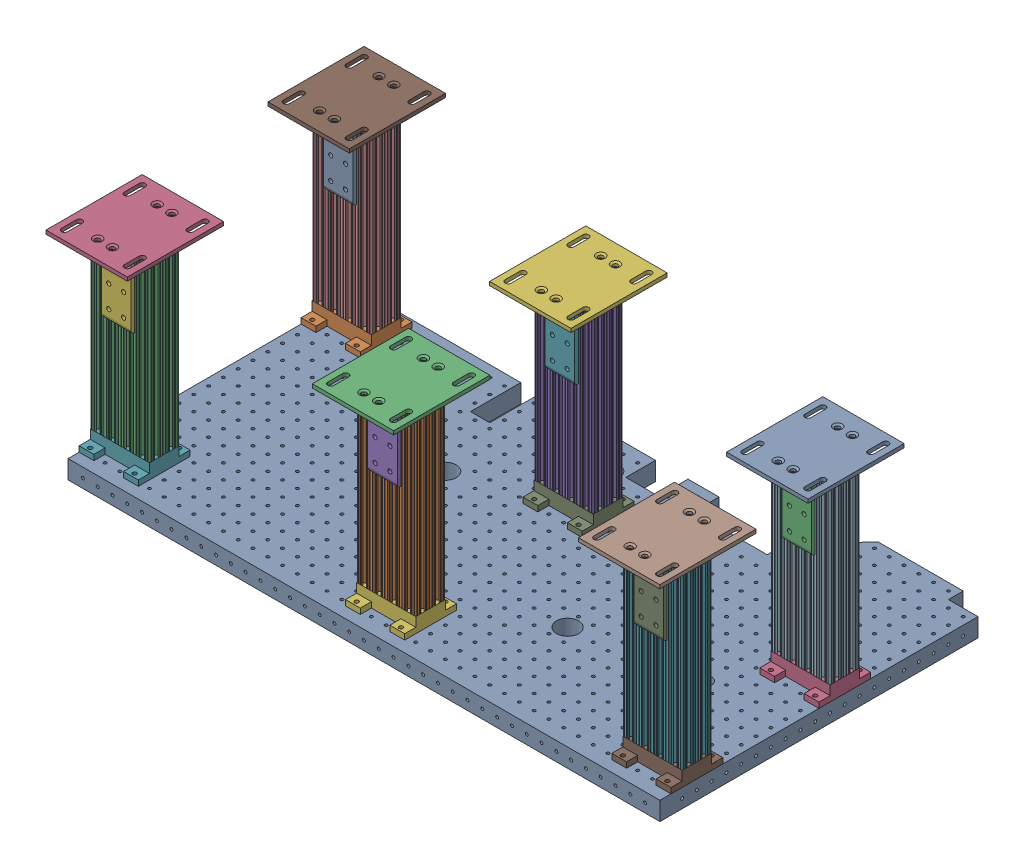
SolidWorks assembly Mirrorbreadboard 2 assembly, configuration Default. Lengths in mm.
Overall size (1054.1 371.48 590.75).
43 component instances, 5 part files, 18 mates.
Components (placement in the parent):
- MirrorBreadboard1-2: MirrorBreadboard1 [Default] at (-194.6573 17.0814 -91.1131) size (1016 31.75 571.5)
- Mirrorbreadboard support leg assembly-2: Mirrorbreadboard support leg assembly [Default] at (-182.8187 304.0452 389.5924) x (0 0 1) z (0 -1 0) size (165.1 139.7 339.72)
  - Mirror8020-2040 leg for breadboard support-1: Mirror8020-2040 leg for breadboard support [Default] at (-48.9055 -77.0614 -78.1612) size (50.8 101.6 307.98)
  - Mirror8020-2387-DEFAULT-1: Mirror8020-2387-DEFAULT [Default] at (-34.9863 -22.6888 -91.8816) x (0 1 0) z (1 0 0) size (139.7 133.35 165.1)
    - Mirror8020-2387-DEFAULT_238708-1: Mirror8020-2387-DEFAULT_238708 [Default] at (-67.1549 7.3704 -27.8119) size (139.7 6.35 165.1)
    - Mirror8020-2387-DEFAULT_238509-1: Mirror8020-2387-DEFAULT_238509 [Default] at (9.1264 0.0214 -49.7635) x (0 0 -1) z (1 0 0) size (50.8 127 50.8)
    - Mirror8020-2387-DEFAULT_238509-2: Mirror8020-2387-DEFAULT_238509 [Default] at (-41.6736 0.0214 46.9187) x (0 0 1) z (-1 0 0) size (50.8 127 50.8)
  - Mirrorbreadboard support leg top bracket-1: Mirrorbreadboard support leg top bracket [Default] at (-61.6055 -89.7614 229.8138) x (0 1 0) z (1 0 0) size (101.6 25.4 88.9)
- Mirrorbreadboard support leg assembly1-2: Mirrorbreadboard support leg assembly1 [Default] at (352.3041 304.0452 317.1813) x (0 0 -1) z (0 -1 0) size (165.1 139.7 339.72)
  - Mirror8020-2040 leg for breadboard support-1: Mirror8020-2040 leg for breadboard support [Default] at (-48.9055 -77.0614 -78.1612) size (50.8 101.6 307.98)
  - Mirror8020-2387-DEFAULT1-1: Mirror8020-2387-DEFAULT1 [Default] at (-34.9863 -22.6888 -91.8816) x (0 1 0) z (1 0 0) size (139.7 133.35 165.1)
    - Mirror8020-2387-DEFAULT_238708-1: Mirror8020-2387-DEFAULT_238708 [Default] at (-67.1549 7.3704 -27.8119) size (139.7 6.35 165.1)
    - Mirror8020-2387-DEFAULT_238509-1: Mirror8020-2387-DEFAULT_238509 [Default] at (9.1264 0.0214 -49.7635) x (0 0 -1) z (1 0 0) size (50.8 127 50.8)
    - Mirror8020-2387-DEFAULT_238509-2: Mirror8020-2387-DEFAULT_238509 [Default] at (-41.6736 0.0214 46.9187) x (0 0 1) z (-1 0 0) size (50.8 127 50.8)
  - Mirrorbreadboard support leg top bracket-1: Mirrorbreadboard support leg top bracket [Default] at (-61.6055 -89.7614 229.8138) x (0 1 0) z (1 0 0) size (101.6 25.4 88.9)
- Mirrorbreadboard support leg assembly2-3: Mirrorbreadboard support leg assembly2 [Default] at (274.3813 304.0452 135.5924) x (0 0 1) z (0 -1 0) size (165.1 139.7 339.72)
  - Mirror8020-2040 leg for breadboard support-1: Mirror8020-2040 leg for breadboard support [Default] at (-48.9055 -77.0614 -78.1612) size (50.8 101.6 307.98)
  - Mirror8020-2387-DEFAULT2-1: Mirror8020-2387-DEFAULT2 [Default] at (-34.9863 -22.6888 -91.8816) x (0 1 0) z (1 0 0) size (139.7 133.35 165.1)
    - Mirror8020-2387-DEFAULT_238708-1: Mirror8020-2387-DEFAULT_238708 [Default] at (-67.1549 7.3704 -27.8119) size (139.7 6.35 165.1)
    - Mirror8020-2387-DEFAULT_238509-1: Mirror8020-2387-DEFAULT_238509 [Default] at (9.1264 0.0214 -49.7635) x (0 0 -1) z (1 0 0) size (50.8 127 50.8)
    - Mirror8020-2387-DEFAULT_238509-2: Mirror8020-2387-DEFAULT_238509 [Default] at (-41.6736 0.0214 46.9187) x (0 0 1) z (-1 0 0) size (50.8 127 50.8)
  - Mirrorbreadboard support leg top bracket-1: Mirrorbreadboard support leg top bracket [Default] at (-61.6055 -89.7614 229.8138) x (0 1 0) z (1 0 0) size (101.6 25.4 88.9)
- Mirrorbreadboard support leg assembly3-4: Mirrorbreadboard support leg assembly3 [Default] at (-104.8959 304.0452 12.3813) x (0 0 -1) z (0 -1 0) size (165.1 139.7 339.72)
  - Mirror8020-2040 leg for breadboard support-1: Mirror8020-2040 leg for breadboard support [Default] at (-48.9055 -77.0614 -78.1612) size (50.8 101.6 307.98)
  - Mirror8020-2387-DEFAULT3-1: Mirror8020-2387-DEFAULT3 [Default] at (-34.9863 -22.6888 -91.8816) x (0 1 0) z (1 0 0) size (139.7 133.35 165.1)
    - Mirror8020-2387-DEFAULT_238708-1: Mirror8020-2387-DEFAULT_238708 [Default] at (-67.1549 7.3704 -27.8119) size (139.7 6.35 165.1)
    - Mirror8020-2387-DEFAULT_238509-1: Mirror8020-2387-DEFAULT_238509 [Default] at (9.1264 0.0214 -49.7635) x (0 0 -1) z (1 0 0) size (50.8 127 50.8)
    - Mirror8020-2387-DEFAULT_238509-2: Mirror8020-2387-DEFAULT_238509 [Default] at (-41.6736 0.0214 46.9187) x (0 0 1) z (-1 0 0) size (50.8 127 50.8)
  - Mirrorbreadboard support leg top bracket-1: Mirrorbreadboard support leg top bracket [Default] at (-61.6055 -89.7614 229.8138) x (0 1 0) z (1 0 0) size (101.6 25.4 88.9)
- Mirrorbreadboard support leg assembly4-5: Mirrorbreadboard support leg assembly4 [Default] at (-640.0187 304.0452 8.5924) x (0 0 1) z (0 -1 0) size (165.1 139.7 339.72)
  - Mirror8020-2040 leg for breadboard support-1: Mirror8020-2040 leg for breadboard support [Default] at (-48.9055 -77.0614 -78.1612) size (50.8 101.6 307.98)
  - Mirror8020-2387-DEFAULT4-1: Mirror8020-2387-DEFAULT4 [Default] at (-34.9863 -22.6888 -91.8816) x (0 1 0) z (1 0 0) size (139.7 133.35 165.1)
    - Mirror8020-2387-DEFAULT_238708-1: Mirror8020-2387-DEFAULT_238708 [Default] at (-67.1549 7.3704 -27.8119) size (139.7 6.35 165.1)
    - Mirror8020-2387-DEFAULT_238509-1: Mirror8020-2387-DEFAULT_238509 [Default] at (9.1264 0.0214 -49.7635) x (0 0 -1) z (1 0 0) size (50.8 127 50.8)
    - Mirror8020-2387-DEFAULT_238509-2: Mirror8020-2387-DEFAULT_238509 [Default] at (-41.6736 0.0214 46.9187) x (0 0 1) z (-1 0 0) size (50.8 127 50.8)
  - Mirrorbreadboard support leg top bracket-1: Mirrorbreadboard support leg top bracket [Default] at (-61.6055 -89.7614 229.8138) x (0 1 0) z (1 0 0) size (101.6 25.4 88.9)
- Mirrorbreadboard support leg assembly5-6: Mirrorbreadboard support leg assembly5 [Default] at (-640.0187 304.0452 389.5924) x (0 0 1) z (0 -1 0) size (165.1 139.7 339.72)
  - Mirror8020-2040 leg for breadboard support-1: Mirror8020-2040 leg for breadboard support [Default] at (-48.9055 -77.0614 -78.1612) size (50.8 101.6 307.98)
  - Mirror8020-2387-DEFAULT5-1: Mirror8020-2387-DEFAULT5 [Default] at (-34.9863 -22.6888 -91.8816) x (0 1 0) z (1 0 0) size (139.7 133.35 165.1)
    - Mirror8020-2387-DEFAULT_238708-1: Mirror8020-2387-DEFAULT_238708 [Default] at (-67.1549 7.3704 -27.8119) size (139.7 6.35 165.1)
    - Mirror8020-2387-DEFAULT_238509-1: Mirror8020-2387-DEFAULT_238509 [Default] at (9.1264 0.0214 -49.7635) x (0 0 -1) z (1 0 0) size (50.8 127 50.8)
    - Mirror8020-2387-DEFAULT_238509-2: Mirror8020-2387-DEFAULT_238509 [Default] at (-41.6736 0.0214 46.9187) x (0 0 1) z (-1 0 0) size (50.8 127 50.8)
  - Mirrorbreadboard support leg top bracket-1: Mirrorbreadboard support leg top bracket [Default] at (-61.6055 -89.7614 229.8138) x (0 1 0) z (1 0 0) size (101.6 25.4 88.9)
Mates (geometry in assembly coordinates):
- Coincident1: coincident anti-aligned: plane of MirrorBreadboard1-2 through (-194.6573 48.8314 416.8869) normal (0 1 0); plane of Mirrorbreadboard support leg assembly-2/Mirrorbreadboard support leg top bracket-1 through (-93.0573 48.8314 378.7869) normal (0 -1 0)
- Parallel1: parallel aligned: plane of MirrorBreadboard1-2 through (-651.8573 17.0814 416.8869) normal (-1 0 0); plane of Mirrorbreadboard support leg assembly-2/Mirrorbreadboard support leg top bracket-1 through (-194.6573 48.8314 327.9869) normal (-1 0 0)
- Coincident2: coincident anti-aligned: plane of MirrorBreadboard1-2 through (-194.6573 48.8314 416.8869) normal (0 1 0); plane of Mirrorbreadboard support leg assembly3-4/Mirrorbreadboard support leg top bracket-1 through (-194.6573 48.8314 23.1869) normal (0 -1 0)
- Parallel2: parallel anti-aligned: plane of MirrorBreadboard1-2 through (-194.6573 48.8314 416.8869) normal (0 0 1); plane of Mirrorbreadboard support leg assembly3-4/Mirrorbreadboard support leg top bracket-1 through (-93.0573 58.3564 4.1369) normal (0 0 -1)
- Coincident3: coincident anti-aligned: plane of MirrorBreadboard1-2 through (-194.6573 48.8314 416.8869) normal (0 1 0); plane of Mirrorbreadboard support leg assembly2-3/Mirrorbreadboard support leg top bracket-1 through (364.1427 48.8314 124.7869) normal (0 -1 0)
- Coincident4: coincident anti-aligned: plane of MirrorBreadboard1-2 through (-194.6573 48.8314 416.8869) normal (0 1 0); plane of Mirrorbreadboard support leg assembly1-2/Mirrorbreadboard support leg top bracket-1 through (262.5427 48.8314 327.9869) normal (0 -1 0)
- Coincident5: coincident aligned: plane of MirrorBreadboard1-2 through (364.1427 48.8314 -91.1131) normal (1 0 0); plane of Mirrorbreadboard support leg assembly1-2/Mirrorbreadboard support leg top bracket-1 through (364.1427 48.8314 378.7869) normal (1 0 0)
- Concentric1: concentric anti-aligned: circle of MirrorBreadboard1-2; circle of Mirrorbreadboard support leg assembly1-2/Mirrorbreadboard support leg top bracket-1
- Concentric2: concentric anti-aligned: circle of MirrorBreadboard1-2; circle of Mirrorbreadboard support leg assembly3-4/Mirrorbreadboard support leg top bracket-1
- Concentric3: concentric anti-aligned: circle of MirrorBreadboard1-2; circle of Mirrorbreadboard support leg assembly-2/Mirrorbreadboard support leg top bracket-1
- Concentric4: concentric anti-aligned: circle of MirrorBreadboard1-2; circle of Mirrorbreadboard support leg assembly2-3/Mirrorbreadboard support leg top bracket-1
- Parallel3: parallel aligned: plane of MirrorBreadboard1-2 through (364.1427 48.8314 -91.1131) normal (1 0 0); plane of Mirrorbreadboard support leg assembly2-3/Mirrorbreadboard support leg top bracket-1 through (364.1427 48.8314 73.9869) normal (1 0 0)
- Coincident6: coincident anti-aligned: plane of MirrorBreadboard1-2 through (-194.6573 48.8314 416.8869) normal (0 1 0); plane of Mirrorbreadboard support leg assembly4-5/Mirrorbreadboard support leg top bracket-1 through (-550.2573 48.8314 -2.2131) normal (0 -1 0)
- Concentric5: concentric anti-aligned: circle of MirrorBreadboard1-2; circle of Mirrorbreadboard support leg assembly4-5/Mirrorbreadboard support leg top bracket-1
- Parallel4: parallel aligned: plane of MirrorBreadboard1-2 through (-651.8573 17.0814 416.8869) normal (-1 0 0); plane of Mirrorbreadboard support leg assembly4-5/Mirrorbreadboard support leg top bracket-1 through (-651.8573 48.8314 -53.0131) normal (-1 0 0)
- Coincident7: coincident anti-aligned: plane of MirrorBreadboard1-2 through (-194.6573 48.8314 416.8869) normal (0 1 0); plane of Mirrorbreadboard support leg assembly5-6/Mirrorbreadboard support leg top bracket-1 through (-550.2573 48.8314 378.7869) normal (0 -1 0)
- Concentric6: concentric anti-aligned: circle of MirrorBreadboard1-2; circle of Mirrorbreadboard support leg assembly5-6/Mirrorbreadboard support leg top bracket-1
- Parallel5: parallel aligned: plane of MirrorBreadboard1-2 through (-651.8573 17.0814 416.8869) normal (-1 0 0); plane of Mirrorbreadboard support leg assembly5-6/Mirrorbreadboard support leg top bracket-1 through (-651.8573 48.8314 327.9869) normal (-1 0 0)
